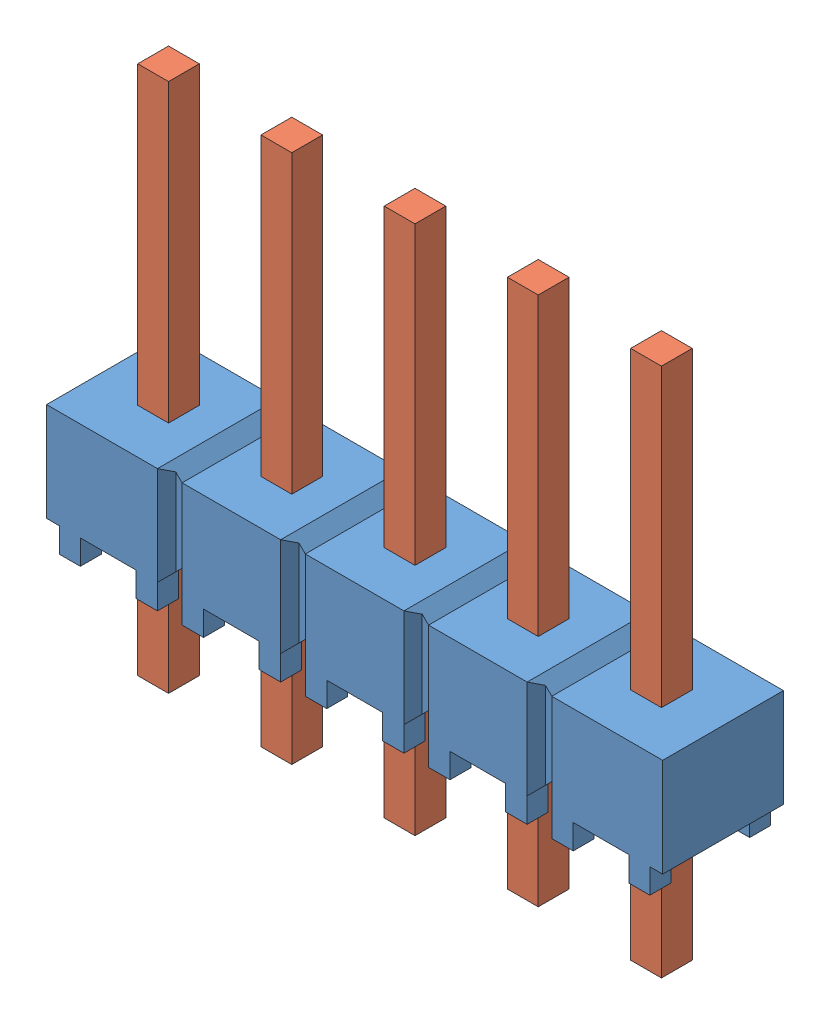
SolidWorks assembly HMTSW_105_07_G_S_240, configuration Default. Lengths in mm.
Overall size (12.7 10.92 2.49).
2 component instances, 2 part files, 0 mates.
Components (placement in the parent):
- _HMTSW_105_07_G_S_240_body_2-1: _HMTSW_105_07_G_S_240_body_2 [Default] at origin size (12.7 2.54 2.49)
- _HMTSW_105_07_S_240_4-1: _HMTSW_105_07_S_240_4 [Default] at (0 -2.286 0) size (11.05 10.92 0.89)
